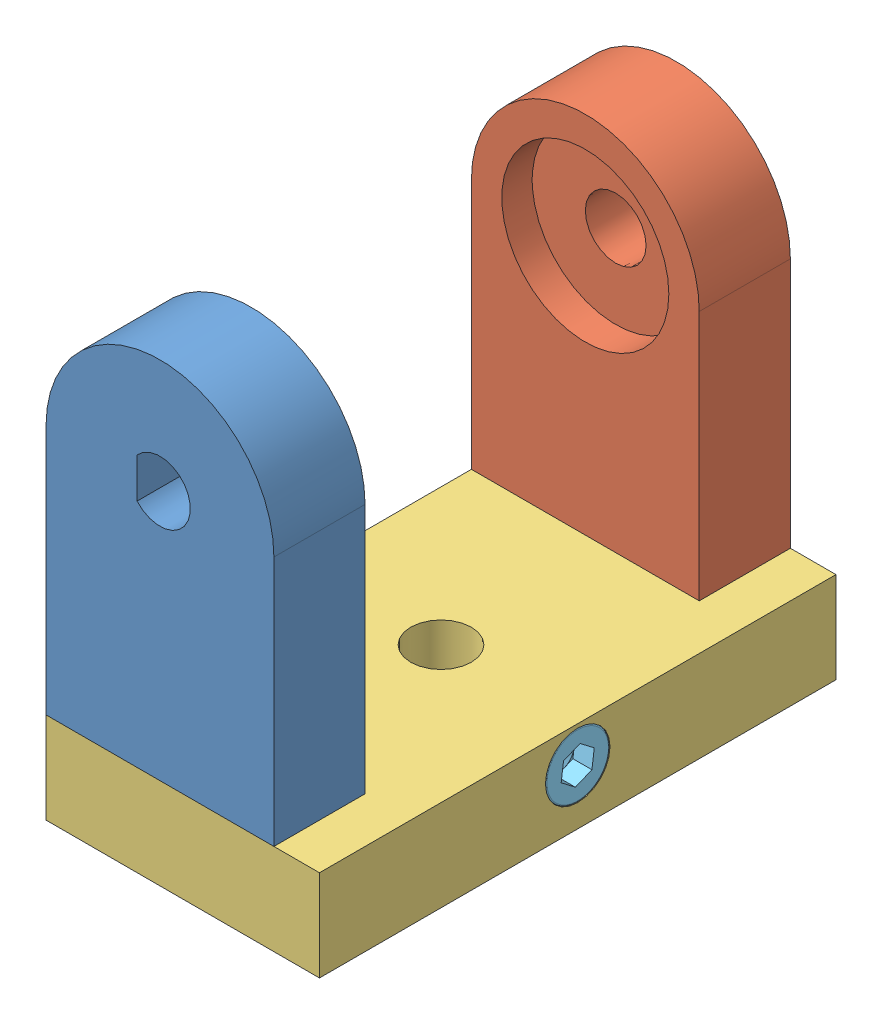
SolidWorks assembly Link4, configuration Default. Lengths in mm.
Overall size (36 60 68.86).
9 component instances, 5 part files, 1 mates.
Components (placement in the parent):
- ConnectingJoint-1: ConnectingJoint [Default] at (-13.0484 0 -9.0061) size (36 60 68.86)
  - BearingJoints-1: BearingJoints [Default] at (10.0484 39.9223 31.0061) size (30 48 12)
  - BearingJoints2-1: BearingJoints2 [Default] at (10.0484 39.9223 -12.9939) x (-1 0 0) z (0 0 -1) size (30 48 12)
  - JointBottom-1: JointBottom [Default] at (13.0484 -5.0777 9.0061) x (0 0 -1) z (1 0 0) size (68 12 36)
  - socket head cap screw_iso-1: socket head cap screw_iso [ISO 4762 M6 x 20 - 20S] at (3.0484 -5.0777 -18.9939) x (0 1 0) z (-0.488199 0 0.872732) size (26 10 10)
  - socket head cap screw_iso-2: socket head cap screw_iso [ISO 4762 M6 x 20 - 20S] at (3.0484 -5.0777 37.0061) x (0 1 0) z (0 0 1) size (26 10 10)
  - socket head cap screw_iso-3: socket head cap screw_iso [ISO 4762 M6 x 20 - 20S] at (17.0484 -5.0777 37.0061) x (0 1 0) z (0 0 1) size (26 10 10)
  - socket head cap screw_iso-4: socket head cap screw_iso [ISO 4762 M6 x 20 - 20S] at (17.0484 -5.0777 -18.9939) x (0 1 0) z (-0.513591 0 0.858035) size (26 10 10)
  - M5X10-1: M5X10 [Default] at (22.2578 2.0842 9.2195) x (-1 0 0) z (0 -0.924225 -0.381849) size (15 8.5 8.5)
Mates (geometry in assembly coordinates):
- Concentric1: concentric: cylinder of ConnectingJoint-1/JointBottom-1 through (0 -1.0777 0) axis (0 -1 0) radius 11
